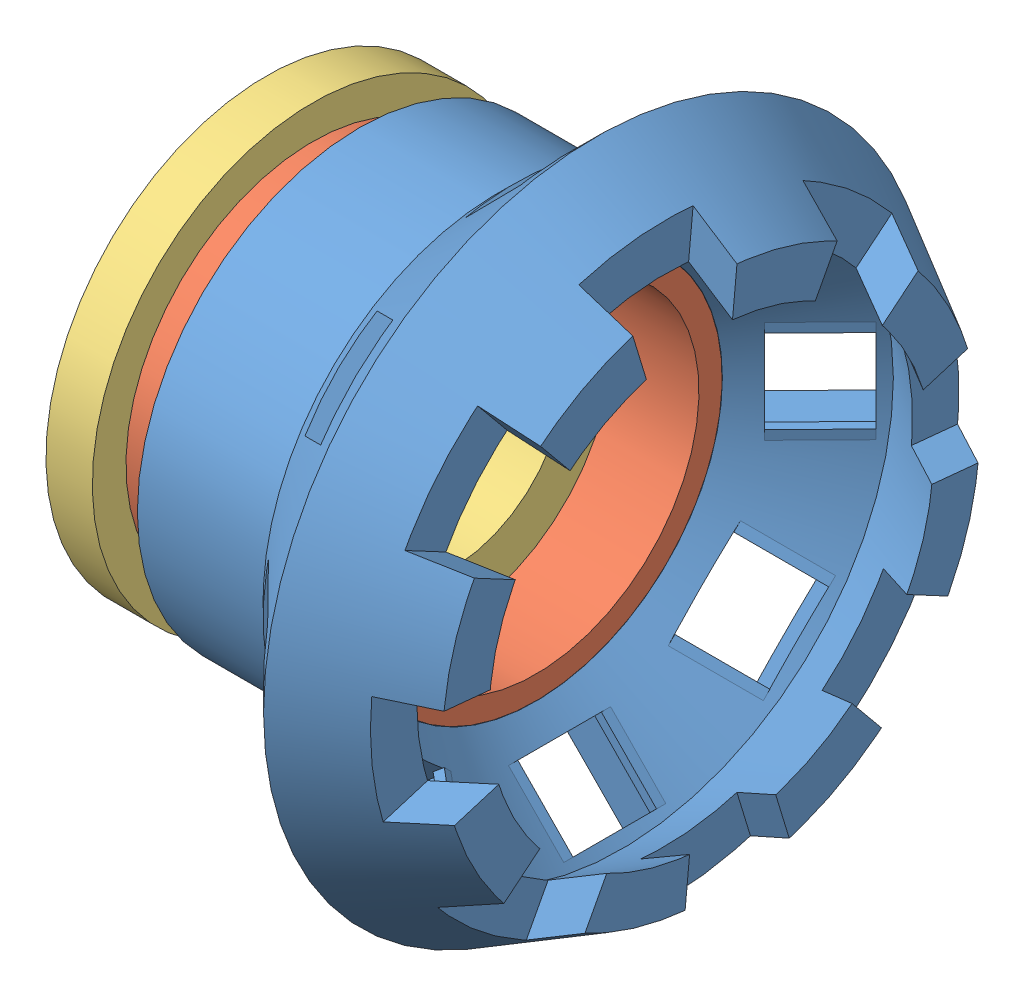
SolidWorks assembly 装配体1, configuration 默认. Lengths in mm.
Overall size (13.25 14.34 14.34).
3 component instances, 3 part files, 4 mates.
Components (placement in the parent):
- 下面3D打印部分-1: 下面3D打印部分 [默认] at origin size (13.25 14.34 14.34)
- 铝环-1: 铝环 [默认] at (-1.426 0 0) x (1 0 0) z (0 -0.037855 -0.999283) size (4.8 9.03 8.05)
- protective_cap-1: protective_cap [默认] at (0.955 0 0) x (0 -0.058338 0.998297) z (-1 0 0) size (9.5 9.5 4)
Mates (geometry in assembly coordinates):
- 同心1: concentric aligned: cylinder of 下面3D打印部分-1 through (0 0 0) axis (-1 0 0) radius 4.03; cylinder of 铝环-1 through (-1.426 0 0) axis (-1 0 0) radius 4.025
- 重合1: coincident anti-aligned: circle of 下面3D打印部分-1; plane of 铝环-1 through (6.755 -4.0221 0.1524) normal (1 0 0)
- 同心2: concentric anti-aligned: cylinder of 铝环-1 through (-1.426 0 0) axis (-1 0 0) radius 3.525; cylinder of protective_cap-1 through (1.955 0 0) axis (1 0 0) radius 3.45
- 重合2: coincident anti-aligned: plane of 铝环-1 through (1.955 -4.0221 0.1524) normal (-1 0 0); plane of protective_cap-1 through (1.955 4.7419 0.2771) normal (1 0 0)
